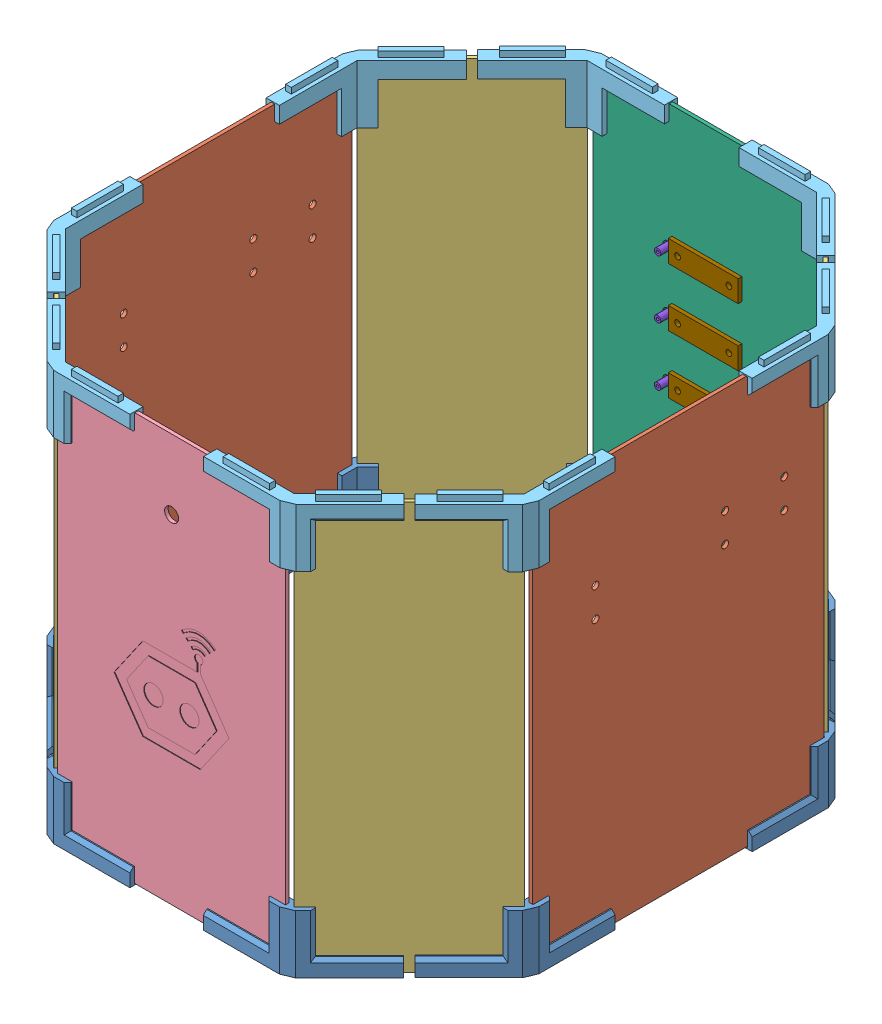
SolidWorks assembly Assem_Body_Pioneer, configuration Default. Lengths in mm.
Overall size (488.28 357 542.29).
41 component instances, 9 part files, 70 mates.
Components (placement in the parent):
- Links_ButtomOfBody-1: Links_ButtomOfBody [Default] at (-117.5632 60.4705 15.387) size (58.32 50 121.51)
- Body_Side_Panel_Pioneer-1: Body_Side_Panel_Pioneer [Default] at (-126.5632 61.4705 267.387) x (0 0 -1) z (0 -1 0) size (250 3 350)
- Body_Angled_Panel_Pioneer-1: Body_Angled_Panel_Pioneer [Default] at (-124.2129 61.4705 12.4372) x (0.707106 0 -0.707108) z (0 -1 0) size (140 3 350)
- Links_ButtomOfBody-2: Links_ButtomOfBody [Default] at (-17.44 60.4705 -81.6082) x (0.707108 0 0.707106) z (-0.707106 0 0.707108) size (58.32 50 121.51)
- Links_ButtomOfBody-3: Links_ButtomOfBody [Default] at (-119.7753 60.4705 264.7707) x (0.707108 0 -0.707106) z (0.707106 0 0.707108) size (58.32 50 121.51)
- Links_ButtomOfBody-4: Links_ButtomOfBody [Default] at (177.9437 60.4705 -79.9967) x (0.000004 0 1) z (-1 0 0.000004) size (58.32 50 121.51)
- Body_Angled_Panel_Pioneer-2: Body_Angled_Panel_Pioneer [Default] at (180.8935 61.4705 -86.6465) x (0.707111 0 0.707103) z (0 -1 0) size (140 3 350)
- Body_Angled_Panel_Pioneer-3: Body_Angled_Panel_Pioneer [Default] at (-124.5129 411.4705 272.3367) x (0.707106 0 0.707108) z (0 1 0) size (140 3 350)
- Links_ButtomOfBody-5: Links_ButtomOfBody [Default] at (275.1514 60.4705 19.914) x (-0.707103 0 0.707111) z (-0.707111 0 -0.707103) size (58.32 50 121.51)
- Links_ButtomOfBody-6: Links_ButtomOfBody [Default] at (-22.5684 60.4705 364.6821) x (0.000004 0 -1) z (1 0 0.000004) size (58.32 50 121.51)
- Body_Back_Panel_Pioneer-2: Body_Back_Panel_Pioneer [Default] at (175.4316 411.4705 370.3828) x (-1 0 -0.000004) z (0 1 0) size (196 3 350)
- Links_ButtomOfBody-7: Links_ButtomOfBody [Default] at (172.8153 60.4705 366.5949) x (-0.707103 0 -0.707111) z (0.707111 0 -0.707103) size (58.32 50 121.51)
- Body_Angled_Panel_Pioneer-4: Body_Angled_Panel_Pioneer [Default] at (180.3813 411.4705 371.3325) x (0.707111 0 -0.707103) z (0 1 0) size (140 3 350)
- Links_ButtomOfBody-8: Links_ButtomOfBody [Default] at (272.5149 60.4705 269.1762) x (-1 0 -0.000007) z (0.000007 0 -1) size (58.32 50 121.51)
- Body_Side_Panel_Pioneer-2: Body_Side_Panel_Pioneer [Default] at (278.215 61.4705 267.1762) x (0.000007 0 -1) z (0 -1 0) size (250 3 350)
- Links_TopOfBody-1: Links_TopOfBody [Default] at (177.4316 412.4705 364.3828) x (0.000004 0 -1) z (-1 0 -0.000004) size (58.32 55 121.51)
- Links_TopOfBody-2: Links_TopOfBody [Default] at (274.6392 412.4705 264.7721) x (-0.707103 0 -0.707111) z (-0.707111 0 0.707103) size (58.32 55 121.51)
- Links_TopOfBody-3: Links_TopOfBody [Default] at (-17.9521 412.4705 366.5942) x (0.707108 0 -0.707106) z (-0.707106 0 -0.707108) size (58.32 55 121.51)
- Links_TopOfBody-4: Links_TopOfBody [Default] at (-117.8632 412.4705 269.387) x (1 0 0) z (0 0 -1) size (58.32 55 121.51)
- Links_TopOfBody-5: Links_TopOfBody [Default] at (-22.9838 412.4705 -79.9955) x (0.000004 0 1) z (1 0 -0.000004) size (58.32 55 121.51)
- Links_TopOfBody-6: Links_TopOfBody [Default] at (-119.7753 412.4705 20.0033) x (0.707108 0 0.707106) z (0.707106 0 -0.707108) size (58.32 55 121.51)
- Links_TopOfBody-7: Links_TopOfBody [Default] at (172.9236 412.4705 -82.3359) x (-0.707103 0 0.707111) z (0.707111 0 0.707103) size (58.32 55 121.51)
- Links_TopOfBody-8: Links_TopOfBody [Default] at (273.2392 412.4705 15.2977) x (-1 0 0.000007) z (0.000007 0 1) size (58.32 55 121.51)
- Front_Panel_aluminiumContact-2: Front_Panel_aluminiumContact [Default] at (252.6479 547.9612 132.0594) x (-1 0 0.000004) z (0 -1 0) size (196 15.57 350)
  - Body_Front_panel_aluContact_Pioneer-1: Body_Front_panel_aluContact_Pioneer [Default] at (76.7034 217.7564 486.4907) size (196 3 350)
  - ContactAluFer-1: ContactAluFer [Default] at (200.8005 260.6088 326.6446) x (-1 0 0) z (0 0 1) size (80 15.57 25.3)
    - Contact_barreAlu-1: Contact_barreAlu [Default] at (-13.9029 35.8024 53.6961) size (80 3.2 25.3)
    - ConnecteurAAnneau-1: ConnecteurAAnneau [Default] at (4.0971 39.0024 66.3461) x (0 0 1) z (-1 0 0) size (11.92 12.37 20.64)
    - Contact_barreFer-1: Contact_barreFer [Default] at (-3.9029 42.8524 75.6811) size (60 3.15 18.67)
  - ContactAluFer-2: ContactAluFer [Default] at (200.8005 260.6088 226.6379) x (-1 0 0) z (0 0 1) size (80 15.57 25.3)
    - Contact_barreAlu-1: Contact_barreAlu [Default] at (-13.9029 35.8024 53.6961) size (80 3.2 25.3)
    - ConnecteurAAnneau-1: ConnecteurAAnneau [Default] at (4.0971 39.0024 66.3461) x (0 0 1) z (-1 0 0) size (11.92 12.37 20.64)
    - Contact_barreFer-1: Contact_barreFer [Default] at (-3.9029 42.8524 75.6811) size (60 3.15 18.67)
  - ContactAluFer-3: ContactAluFer [Default] at (200.8005 260.6088 276.6446) x (-1 0 0) z (0 0 1) size (80 15.57 25.3)
    - Contact_barreAlu-1: Contact_barreAlu [Default] at (-13.9029 35.8024 53.6961) size (80 3.2 25.3)
    - ConnecteurAAnneau-1: ConnecteurAAnneau [Default] at (4.0971 39.0024 66.3461) x (0 0 1) z (-1 0 0) size (11.92 12.37 20.64)
    - Contact_barreFer-1: Contact_barreFer [Default] at (-3.9029 42.8524 75.6811) size (60 3.15 18.67)
  - ContactAluFer-4: ContactAluFer [Default] at (200.8005 260.6088 176.7387) x (-1 0 0) z (0 0 1) size (80 15.57 25.3)
    - Contact_barreAlu-1: Contact_barreAlu [Default] at (-13.9029 35.8024 53.6961) size (80 3.2 25.3)
    - ConnecteurAAnneau-1: ConnecteurAAnneau [Default] at (4.0971 39.0024 66.3461) x (0 0 1) z (-1 0 0) size (11.92 12.37 20.64)
    - Contact_barreFer-1: Contact_barreFer [Default] at (-3.9029 42.8524 75.6811) size (60 3.15 18.67)
Mates (geometry in assembly coordinates):
- Coincident51: coincident anti-aligned: line of Top_plate-1 through (-42.3382 100.5837 240.4468) axis (0.707107 0 0.707107); line of Top_angle-1 through (-7.3679 100.5837 275.4172) axis (-0.707107 0 -0.707107)
- Coincident53: coincident: point of Top_court-1; line of Top_plate-1 through (-42.3382 100.5837 146.1247) axis (0 0 1)
- Coincident54: coincident: line of Top_plate-1 through (-42.3382 103.5837 240.4468) axis (0 -1 0); point of Top_court-1
- Angle3: planar angle = 2.356194 rad aligned: plane of Top_plate-1 through (-10.005 100.5837 279.144) normal (0 -1 0); plane of Top_court-1 through (-115.1702 31.9943 281.8682) normal (-0.707107 0.707107 0)
- Coincident59: coincident anti-aligned: plane of CoinButtom_Bas-1 through (-112.8992 110.4705 5.3661) normal (-0.707108 0 -0.707106); plane of Side_angle-1 through (-122.0916 61.4705 14.5585) normal (0.707108 0 0.707106)
- Coincident60: coincident anti-aligned: plane of CoinButtom_Bas-1 through (-112.8992 61.4705 5.3661) normal (0 1 0); plane of Side_angle-1 through (-122.0916 61.4705 14.5585) normal (0 -1 0)
- Coincident61: coincident anti-aligned: plane of CoinButtom_Bas-1 through (-122.0916 110.4705 14.5585) normal (0.707106 0 -0.707108); plane of Side_angle-1 through (-122.0916 61.4705 14.5585) normal (-0.707106 0 0.707108)
- Coincident62: coincident anti-aligned: plane of CoinButtom_Bas-2 through (-25.2181 110.4705 -86.5579) normal (0.707108 0 0.707106); plane of Side_angle-1 through (-124.2129 61.4705 12.4372) normal (-0.707108 0 -0.707106)
- Coincident63: coincident anti-aligned: plane of Side_angle-1 through (-23.0968 61.4705 -84.4366) normal (0.707106 0 -0.707108); plane of CoinButtom_Bas-2 through (-22.8847 110.4705 -84.2245) normal (-0.707106 0 0.707108)
- Coincident64: coincident anti-aligned: plane of Side_angle-1 through (-122.0916 61.4705 14.5585) normal (0 -1 0); plane of CoinButtom_Bas-2 through (-32.0771 61.4705 -75.032) normal (0 1 0)
- Coincident69: coincident anti-aligned: plane of CoinButtom_Bas-2 through (-20.0563 110.4705 -88.696) normal (0.000004 0 1); plane of Side_court_v-1 through (-20.0563 461.4705 -88.696) normal (-0.000004 0 -1)
- Coincident70: coincident anti-aligned: plane of CoinButtom_Bas-2 through (-7.0563 61.4705 -85.3961) normal (0 1 0); plane of Side_court_v-1 through (-20.0563 61.4705 -88.696) normal (0 -1 0)
- Coincident71: coincident anti-aligned: plane of CoinButtom_Bas-2 through (-20.0563 110.4705 -85.396) normal (1 0 -0.000004); plane of Side_court_v-1 through (-20.0563 461.4705 -88.696) normal (-1 0 0.000004)
- Coincident72: coincident anti-aligned: plane of Side_court_v-1 through (-20.0563 461.4705 -85.696) normal (0.000004 0 1); plane of CoinButtom_Bas-4 through (162.9437 110.4705 -85.6967) normal (-0.000004 0 -1)
- Coincident73: coincident anti-aligned: plane of Side_court_v-1 through (-20.0563 61.4705 -88.696) normal (0 -1 0); plane of CoinButtom_Bas-4 through (162.9437 61.4705 -85.6967) normal (0 1 0)
- Coincident74: coincident anti-aligned: plane of Side_court_v-1 through (175.9437 461.4705 -88.6967) normal (1 0 -0.000004); plane of CoinButtom_Bas-4 through (175.9437 110.4705 -85.6967) normal (-1 0 0.000004)
- Coincident75: coincident anti-aligned: plane of CoinButtom_Bas-4 through (187.9646 110.4705 -75.3328) normal (0.707103 0 -0.707111); plane of Side_angle-2 through (178.7722 61.4705 -84.5252) normal (-0.707103 0 0.707111)
- Coincident76: coincident anti-aligned: plane of CoinButtom_Bas-4 through (187.9646 61.4705 -75.3328) normal (0 1 0); plane of Side_angle-2 through (178.7722 61.4705 -84.5252) normal (0 -1 0)
- Coincident77: coincident anti-aligned: plane of CoinButtom_Bas-4 through (178.7722 110.4705 -84.5252) normal (0.707111 0 0.707103); plane of Side_angle-2 through (178.7722 61.4705 -84.5252) normal (-0.707111 0 -0.707103)
- Coincident79: coincident anti-aligned: plane of CoinButtom_Bas-3 through (-113.1992 110.4705 279.4078) normal (-0.707108 0 0.707106); plane of Side_angle-3 through (-122.3916 411.4705 270.2154) normal (0.707108 0 -0.707106)
- Coincident80: coincident anti-aligned: plane of CoinButtom_Bas-3 through (-122.3916 110.4705 270.2154) normal (0.707106 0 0.707108); plane of Side_angle-3 through (-122.3916 411.4705 270.2154) normal (-0.707106 0 -0.707108)
- Coincident81: coincident anti-aligned: plane of CoinButtom_Bas-3 through (-113.1992 61.4705 279.4078) normal (0 1 0); plane of Side_angle-3 through (-122.3916 61.4705 270.2154) normal (0 -1 0)
- Coincident82: coincident anti-aligned: plane of Side_angle-2 through (178.7722 61.4705 -84.5252) normal (-0.707103 0 0.707111); plane of CoinButtom_Bas-5 through (268.5752 110.4705 5.2769) normal (0.707103 0 -0.707111)
- Coincident83: coincident anti-aligned: plane of Side_angle-2 through (277.7676 61.4705 14.4693) normal (0.707111 0 0.707103); plane of CoinButtom_Bas-5 through (277.7676 110.4705 14.4693) normal (-0.707111 0 -0.707103)
- Coincident84: coincident anti-aligned: plane of Side_angle-2 through (178.7722 61.4705 -84.5252) normal (0 -1 0); plane of CoinButtom_Bas-5 through (268.5752 61.4705 5.2769) normal (0 1 0)
- Coincident85: coincident anti-aligned: plane of Side_angle-3 through (-122.3916 411.4705 270.2154) normal (0.707108 0 -0.707106); plane of CoinButtom_Bas-6 through (-32.5892 110.4705 360.0181) normal (-0.707108 0 0.707106)
- Coincident86: coincident anti-aligned: plane of Side_angle-3 through (-122.3916 61.4705 270.2154) normal (0 -1 0); plane of CoinButtom_Bas-6 through (-32.5892 61.4705 360.0181) normal (0 1 0)
- Coincident87: coincident anti-aligned: plane of Side_angle-3 through (-23.3968 411.4705 369.2105) normal (0.707106 0 0.707108); plane of CoinButtom_Bas-6 through (-23.3968 110.4705 369.2105) normal (-0.707106 0 -0.707108)
- Coincident88: coincident anti-aligned: plane of CoinButtom_Bas-6 through (-7.5684 110.4705 370.3821) normal (-0.000004 0 1); plane of Side_court_v-2 through (175.4316 411.4705 370.3828) normal (0.000004 0 -1)
- Coincident89: coincident anti-aligned: plane of CoinButtom_Bas-6 through (-20.5684 110.4705 370.3821) normal (1 0 0.000004); plane of Side_court_v-2 through (-20.5684 411.4705 373.3821) normal (-1 0 -0.000004)
- Coincident90: coincident anti-aligned: plane of CoinButtom_Bas-6 through (-7.5684 61.4705 370.3821) normal (0 1 0); plane of Side_court_v-2 through (175.4316 61.4705 373.3828) normal (0 -1 0)
- Coincident91: coincident anti-aligned: plane of Side_court_v-2 through (175.4316 411.4705 370.3828) normal (0.000004 0 -1); plane of CoinButtom_Bas-7 through (162.4316 110.4705 370.3827) normal (-0.000004 0 1)
- Coincident92: coincident anti-aligned: plane of Side_court_v-2 through (175.4316 61.4705 373.3828) normal (0 -1 0); plane of CoinButtom_Bas-7 through (162.4316 61.4705 370.3827) normal (0 1 0)
- Coincident93: coincident anti-aligned: plane of Side_court_v-2 through (175.4316 411.4705 373.3828) normal (1 0 0.000004); plane of CoinButtom_Bas-7 through (175.4316 110.4705 370.3828) normal (-1 0 -0.000004)
- Coincident94: coincident anti-aligned: plane of CoinButtom_Bas-7 through (187.4525 110.4705 360.0189) normal (0.707103 0 0.707111); plane of Side_angle-4 through (178.26 411.4705 369.2112) normal (-0.707103 0 -0.707111)
- Coincident95: coincident anti-aligned: plane of CoinButtom_Bas-7 through (178.26 110.4705 369.2112) normal (0.707111 0 -0.707103); plane of Side_angle-4 through (178.26 411.4705 369.2112) normal (-0.707111 0 0.707103)
- Coincident96: coincident anti-aligned: plane of CoinButtom_Bas-7 through (187.4525 61.4705 360.0189) normal (0 1 0); plane of Side_angle-4 through (178.26 61.4705 369.2112) normal (0 -1 0)
- Coincident97: coincident anti-aligned: plane of Side_angle-4 through (180.3813 411.4705 371.3325) normal (0.707103 0 0.707111); plane of CoinButtom_Bas-8 through (279.3768 110.4705 272.3381) normal (-0.707103 0 -0.707111)
- Coincident98: coincident anti-aligned: plane of Side_angle-4 through (178.26 61.4705 369.2112) normal (0 -1 0); plane of CoinButtom_Bas-8 through (267.8509 61.4705 279.197) normal (0 1 0)
- Coincident99: coincident anti-aligned: plane of Side_angle-4 through (277.2555 411.4705 270.2168) normal (0.707111 0 -0.707103); plane of CoinButtom_Bas-8 through (277.0434 110.4705 270.0047) normal (-0.707111 0 0.707103)
- Coincident103: coincident anti-aligned: plane of CoinButtom_Bas-8 through (278.215 110.4705 254.1762) normal (1 0 0.000007); plane of Body_Side_Panel-2 through (278.215 61.4705 267.1762) normal (-1 0 -0.000007)
- Coincident104: coincident anti-aligned: plane of CoinButtom_Bas-8 through (278.215 61.4705 254.1762) normal (0 1 0); plane of Body_Side_Panel-2 through (281.215 61.4705 267.1763) normal (0 -1 0)
- Coincident105: coincident anti-aligned: plane of CoinButtom_Bas-8 through (278.215 110.4705 267.1762) normal (0.000007 0 -1); plane of Body_Side_Panel-2 through (281.215 61.4705 267.1763) normal (-0.000007 0 1)
- Coincident106: coincident anti-aligned: plane of Side_court_v-2 through (175.4316 411.4705 373.3828) normal (-0.000004 0 1); plane of Links_TopOfBody-1 through (175.4316 362.4705 373.3828) normal (0.000004 0 -1)
- Coincident107: coincident anti-aligned: plane of Side_court_v-2 through (175.4316 411.4705 373.3828) normal (0 1 0); plane of Links_TopOfBody-1 through (162.4316 411.4705 370.0827) normal (0 -1 0)
- Coincident108: coincident anti-aligned: plane of Side_court_v-2 through (175.4316 411.4705 373.3828) normal (1 0 0.000004); plane of Links_TopOfBody-1 through (175.4316 362.4705 370.0828) normal (-1 0 -0.000004)
- Coincident109: coincident anti-aligned: plane of Side_angle-4 through (178.26 411.4705 369.2112) normal (-0.707103 0 -0.707111); plane of Links_TopOfBody-2 through (268.0631 362.4705 279.4091) normal (0.707103 0 0.707111)
- Coincident110: coincident anti-aligned: plane of Side_angle-4 through (277.2555 411.4705 270.2168) normal (0.707111 0 -0.707103); plane of Links_TopOfBody-2 through (277.2555 362.4705 270.2168) normal (-0.707111 0 0.707103)
- Coincident111: coincident anti-aligned: plane of Side_angle-4 through (178.26 411.4705 369.2112) normal (0 1 0); plane of Links_TopOfBody-2 through (268.0631 411.4705 279.4091) normal (0 -1 0)
- Coincident113: coincident anti-aligned: plane of Side_court_v-2 through (175.4316 411.4705 370.3828) normal (0.000004 0 -1); plane of Links_TopOfBody-3 through (-7.5684 362.4705 370.3821) normal (-0.000004 0 1)
- Coincident114: coincident anti-aligned: plane of Side_court_v-2 through (175.4316 411.4705 373.3828) normal (0 1 0); plane of Links_TopOfBody-3 through (-7.5684 411.4705 370.3821) normal (0 -1 0)
- Coincident115: coincident anti-aligned: plane of Side_court_v-2 through (-20.5684 411.4705 373.3821) normal (-1 0 -0.000004); plane of Links_TopOfBody-3 through (-20.5684 362.4705 370.3821) normal (1 0 0.000004)
- Coincident116: coincident anti-aligned: plane of Side_angle-3 through (-122.3916 411.4705 270.2154) normal (0.707108 0 -0.707106); plane of Links_TopOfBody-4 through (-113.1992 362.4705 279.4078) normal (-0.707108 0 0.707106)
- Coincident117: coincident anti-aligned: plane of Side_angle-3 through (-122.3916 411.4705 270.2154) normal (-0.707106 0 -0.707108); plane of Links_TopOfBody-4 through (-122.3916 362.4705 270.2154) normal (0.707106 0 0.707108)
- Coincident118: coincident anti-aligned: plane of Side_angle-3 through (-122.3916 411.4705 270.2154) normal (0 1 0); plane of Links_TopOfBody-4 through (-113.1992 411.4705 279.4078) normal (0 -1 0)
- Coincident119: coincident anti-aligned: plane of Side_court_v-1 through (-20.0563 461.4705 -85.696) normal (0.000004 0 1); plane of Links_TopOfBody-5 through (-7.9839 362.4705 -85.6956) normal (-0.000004 0 -1)
- Coincident120: coincident anti-aligned: plane of Side_court_v-1 through (-20.0563 461.4705 -88.696) normal (0 1 0); plane of Links_TopOfBody-5 through (-7.9839 411.4705 -85.6956) normal (0 -1 0)
- Coincident121: coincident anti-aligned: plane of Side_court_v-1 through (-20.0563 461.4705 -88.696) normal (-1 0 0.000004); plane of Links_TopOfBody-5 through (-20.9839 362.4705 -85.6955) normal (1 0 -0.000004)
- Coincident125: coincident anti-aligned: plane of Side_court_v-1 through (-20.0563 461.4705 -85.696) normal (0.000004 0 1); plane of Links_TopOfBody-7 through (162.5399 362.4705 -86.1237) normal (-0.000004 0 -1)
- Coincident126: coincident anti-aligned: plane of Side_court_v-1 through (175.9437 461.4705 -88.6967) normal (1 0 -0.000004); plane of Links_TopOfBody-7 through (175.5399 362.4705 -86.1237) normal (-1 0 0.000004)
- Coincident127: coincident anti-aligned: plane of Side_court_v-1 through (-20.0563 461.4705 -88.696) normal (0 1 0); plane of Links_TopOfBody-7 through (162.5399 411.4705 -86.1237) normal (0 -1 0)
- Coincident128: coincident anti-aligned: plane of Side_angle-2 through (178.7722 61.4705 -84.5252) normal (-0.707103 0 0.707111); plane of Links_TopOfBody-8 through (268.5752 362.4705 5.2769) normal (0.707103 0 -0.707111)
- Coincident129: coincident anti-aligned: plane of Side_angle-2 through (277.7676 61.4705 14.4693) normal (0.707111 0 0.707103); plane of Links_TopOfBody-8 through (277.7676 362.4705 14.4693) normal (-0.707111 0 -0.707103)
- Coincident130: coincident anti-aligned: plane of Side_angle-2 through (178.7722 411.4705 -84.5252) normal (0 1 0); plane of Links_TopOfBody-8 through (268.5752 411.4705 5.2769) normal (0 -1 0)
- Coincident131: coincident anti-aligned: plane of Links_ButtomOfBody-2 through (-20.0563 110.4705 -88.696) normal (0.000004 0 1); plane of charge-1/Side_court_avant-1 through (175.9437 61.4705 -88.6967) normal (-0.000004 0 -1)
- Coincident132: coincident anti-aligned: plane of Links_ButtomOfBody-2 through (-7.0563 61.4705 -85.3961) normal (0 1 0); plane of charge-1/Side_court_avant-1 through (175.9437 61.4705 -88.6967) normal (0 -1 0)
- Coincident133: coincident anti-aligned: plane of Links_ButtomOfBody-2 through (-20.0563 110.4705 -85.396) normal (1 0 -0.000004); plane of charge-1/Side_court_avant-1 through (-20.0563 61.4705 -88.696) normal (-1 0 0.000004)
- Coincident134: coincident anti-aligned: plane of Side_angle-2 through (178.7722 411.4705 -84.5252) normal (0 1 0); plane of Links_TopOfBody-7 through (187.5608 411.4705 -75.7598) normal (0 -1 0)
- Coincident135: coincident anti-aligned: plane of Links_TopOfBody-5 through (-7.9839 411.4705 -85.6956) normal (0 -1 0); plane of charge-1/Side_court_avant-1 through (175.9437 411.4705 -88.6967) normal (0 1 0)
- Coincident140: coincident anti-aligned: plane of Links_ButtomOfBody-1 through (-126.5632 110.4705 17.387) normal (1 0 0); plane of Body_Side_Panel-1 through (-126.5632 61.4705 267.387) normal (-1 0 0)
